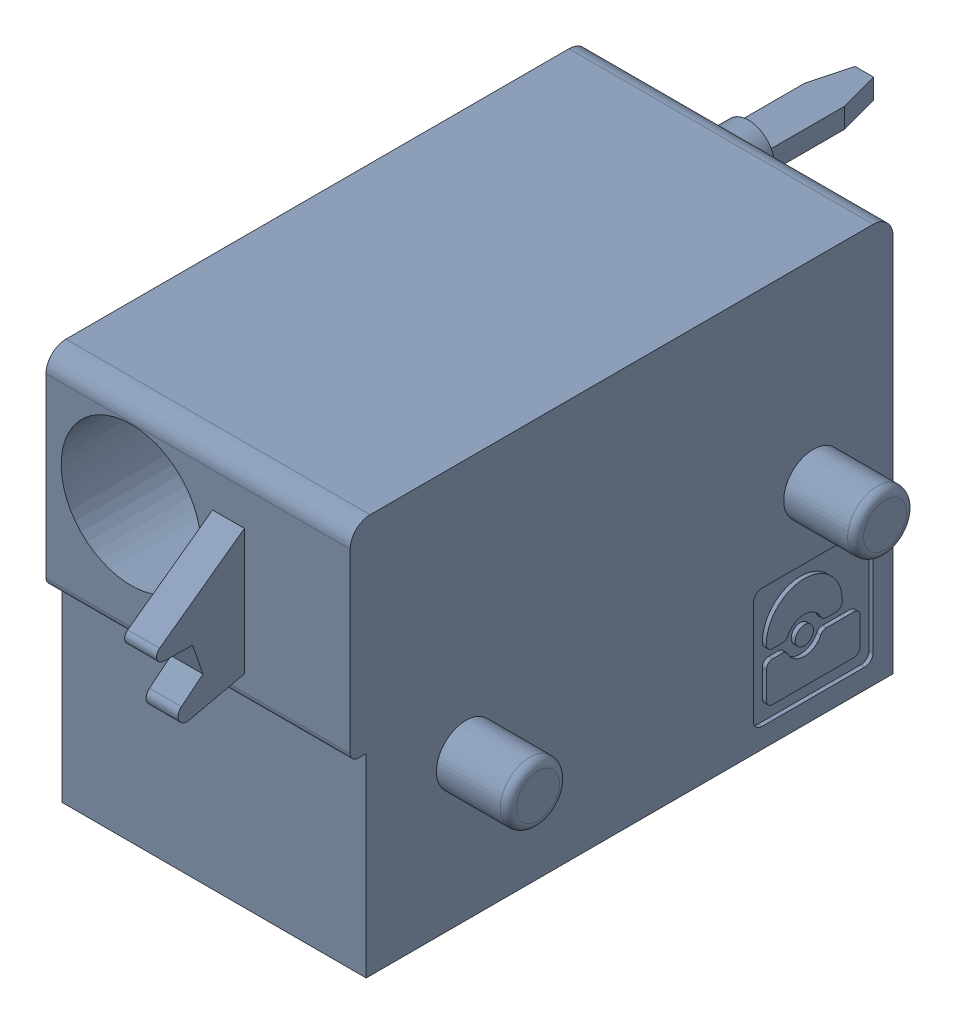
SolidWorks assembly J23, configuration Default. Lengths in mm.
Overall size (9.42 10 19.2).
2 component instances, 1 part files, 0 mates.
Components (placement in the parent):
- 1790377-1: 1790377 [Default] at (52.7051 -7.6199 0) x (0 1 0) z (1 0 0) size (10 19.2 9.42)
  - ffkdsa-v2-7.62-1: ffkdsa-v2-7.62 [Default] at (-23.7414 -38.158 -5.08) x (0 -1 0) z (0 0 1) size (19.2 10 9.42)
